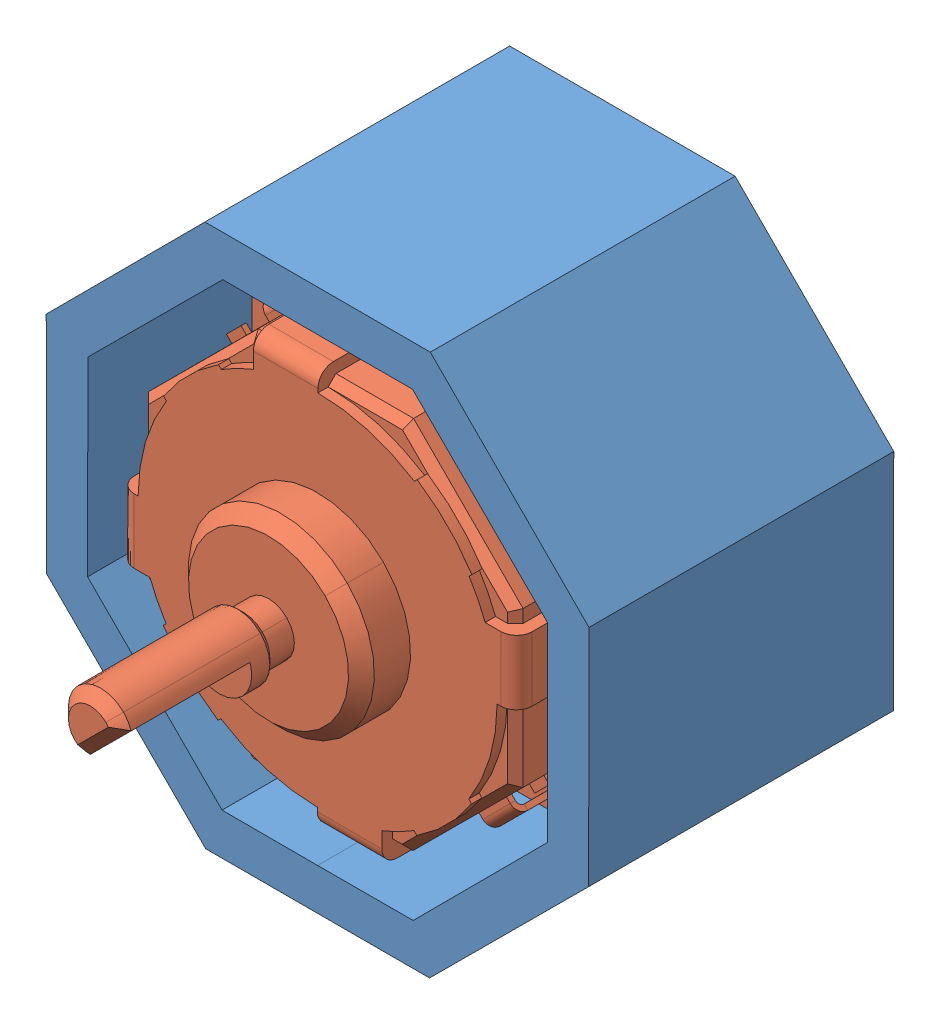
SolidWorks assembly Assem3, configuration Default. Lengths in mm.
Overall size (24.32 24.32 20.62).
2 component instances, 2 part files, 4 mates.
Components (placement in the parent):
- mount with lock-1: mount with lock [Default] at (-1.4806 -1.2601 -3.4583) size (21.01 21 11.8)
- funkySwitch-1: funkySwitch [Default] at (4.8263 12.7793 13.7931) x (-0.708135 -0.706077 0) z (0 0 1) size (17.2 17.2 20.62)
Mates (geometry in assembly coordinates):
- Coincident1: coincident anti-aligned: plane of mount with lock-1 through (10.3432 30.3348 13.7931) normal (0 0 1); plane of funkySwitch-1 through (-2.5571 16.856 13.7931) normal (0 0 -1)
- Distance1: distance = 0.295 mm: plane of mount with lock-1 through (13.7209 16.4788 12.5931) normal (-0.999999 -0.001455 0); plane of funkySwitch-1 through (12.1468 18.7113 16.3431) normal (0.999999 -0.001455 0)
- Distance2: distance = 0.295 mm anti-aligned: plane of mount with lock-1 through (4.8263 21.6794 12.5931) normal (-0.001455 -0.999999 0); plane of funkySwitch-1 through (0.4897 24.2631 16.3431) normal (0.001455 0.999999 0)
- Concentric1: concentric anti-aligned: circle of mount with lock-1; cylinder of funkySwitch-1 through (4.8263 12.7793 24.2931) axis (0 0 -1) radius 3.6
